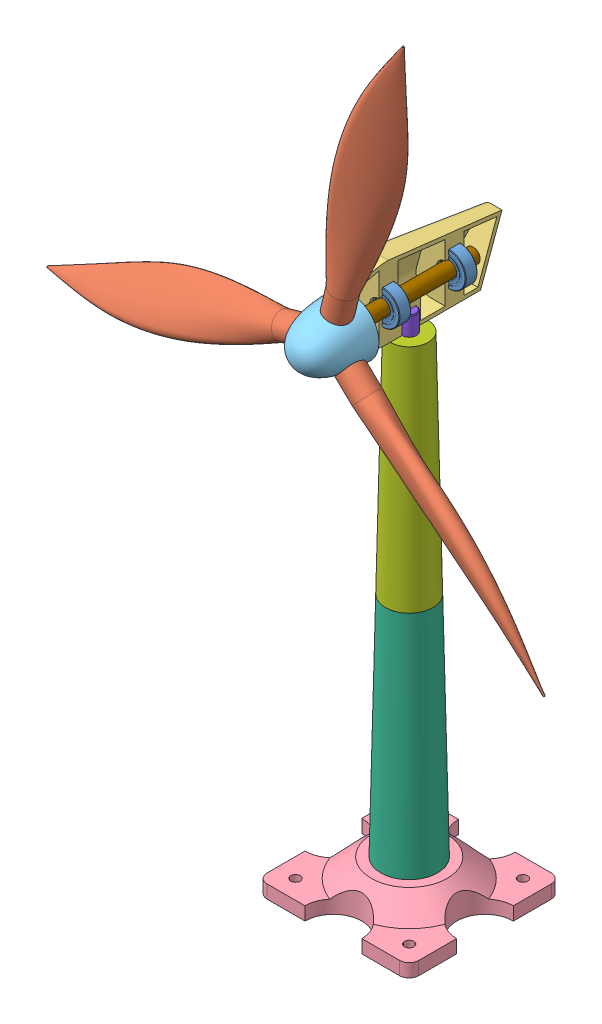
SolidWorks assembly WindTurbine, configuration Default. Lengths in mm.
Overall size (355.91 547.34 141.48).
12 component instances, 9 part files, 20 mates.
Components (placement in the parent):
- 6384K56_Ball Bearing-1: 6384K56_Ball Bearing [6384K56] at origin size (23.02 23.02 7.94)
- blade-1: blade [Default] at (5.4942 -5.28 37.9413) x (0.651126 0.677538 0.34202) z (0.23699 0.246604 -0.939693) size (42.91 190.51 16.85)
- Nacelle turbine-1: Nacelle turbine [Default] at (0 0 -0.1588) size (28.12 50.72 103.39)
- Turbine Base-1: Turbine Base [Default] at (0 -349.25 -14.1288) size (101.6 21.59 101.6)
- turbine hub-1: turbine hub [Default] at (0 0 63.3413) x (-0.692914 -0.721021 0) z (0 0 1) size (38.26 38.57 38.1)
- wind turbine lower mast-1: wind turbine lower mast [Default] at (0 -340.36 -14.1288) x (0 1 0) z (0 0 1) size (165.1 38.1 38.1)
- wind turbine upper mast-1: wind turbine upper mast [Default] at (0 -175.26 -14.1288) x (0 1 0) z (0 0 1) size (165.1 31.75 31.75)
- 6384K56_Ball Bearing-2: 6384K56_Ball Bearing [6384K56] at (0 0 -44.45) size (23.02 23.02 7.94)
- blade-5: blade [Default] at (-7.3197 -2.1181 37.9413) x (0.261202 -0.90266 0.34202) z (0.09507 -0.328541 -0.939693) size (42.91 190.51 16.85)
- blade-6: blade [Default] at (1.8255 7.3981 37.9413) x (-0.912328 0.225122 0.34202) z (-0.33206 0.081938 -0.939693) size (42.91 190.51 16.85)
- wind turbine swivel-2: wind turbine swivel [Default] at (0 -29.21 -14.1288) size (9.65 38.1 9.65)
- wind turbine main shaft-2: wind turbine main shaft [Default] at (0 0 -9.6837) x (1 0 0) z (0 -1 0) size (9.65 95.25 9.65)
Mates (geometry in assembly coordinates):
- Concentric1: concentric anti-aligned: cylinder of Turbine Base-1 through (0 -340.36 -14.1288) axis (0 1 0) radius 19.05; cylinder of wind turbine lower mast-1 through (0 -340.36 -14.1288) axis (0 -1 0) radius 19.05
- Coincident1: coincident anti-aligned: plane of Turbine Base-1 through (0 -340.36 -14.1288) normal (0 1 0); plane of wind turbine lower mast-1 through (-19.05 -340.36 -14.1288) normal (0 -1 0)
- Coincident3: coincident anti-aligned: plane of wind turbine lower mast-1 through (0 -187.96 -14.1288) normal (0 1 0); plane of wind turbine upper mast-1 through (0 -187.96 -14.1288) normal (0 -1 0)
- Coincident4: coincident aligned: cone of wind turbine lower mast-1 through (0 -175.26 -14.1288) axis (0 1 0); cone of wind turbine upper mast-1 through (0 -22.86 -14.1288) axis (0 1 0)
- Tangent1: tangent: plane of assembly; face of Nacelle turbine-1; plane of wind turbine upper mast-1 through (0 -22.86 -14.1288) normal (0 1 0)
- Concentric2: concentric anti-aligned: cylinder of Nacelle turbine-1 through (0 -22.86 -14.1288) axis (0 -1 0) radius 4.826; cylinder of wind turbine upper mast-1 through (0 -48.26 -14.1288) axis (0 1 0) radius 4.826
- Concentric3: concentric aligned: circle of Nacelle turbine-1; circle of turbine hub-1
- Coincident5: coincident anti-aligned: plane of Nacelle turbine-1 through (0 0 25.2413) normal (0 0 1); plane of turbine hub-1 through (0 0 25.2413) normal (0 0 -1)
- Coincident6: coincident anti-aligned: plane of blade-1 through (5.4942 -5.28 37.9413) normal (-0.721021 0.692914 0); plane of turbine hub-1 through (5.4942 -5.28 37.9413) normal (0.721021 -0.692914 0)
- Concentric4: concentric aligned: cylinder of blade-1 through (23.8081 -22.88 37.9413) axis (-0.721021 0.692914 0) radius 8.255; cylinder of turbine hub-1 through (17.2151 -16.544 37.9413) axis (-0.721021 0.692914 0) radius 8.255
- Concentric5: concentric aligned: cylinder of 6384K56_Ball Bearing-1 through (0 0 3.9688) axis (0 0 1) radius 4.7625; cylinder of Nacelle turbine-1 through (0 0 33.2282) axis (0 0 1) radius 11.43
- Coincident7: coincident anti-aligned: plane of 6384K56_Ball Bearing-1 through (0 11.1125 -3.9688) normal (0 0 -1); plane of Nacelle turbine-1 through (0 5.8691 -3.9688) normal (0 0 1)
- Parallel1: parallel anti-aligned: plane of Turbine Base-1 through (-44.45 -349.25 30.3213) normal (0 -1 0)
- Concentric11: concentric aligned: cylinder of Nacelle turbine-1 through (0 0 33.2282) axis (0 0 1) radius 11.43; cylinder of 6384K56_Ball Bearing-2 through (0 0 -40.4813) axis (0 0 1) radius 11.5094
- Coincident13: coincident anti-aligned: plane of Nacelle turbine-1 through (0 5.8691 -48.4188) normal (0 0 1); plane of 6384K56_Ball Bearing-2 through (0 11.1125 -48.4188) normal (0 0 -1)
- Angle5: planar angle = 5.061455 rad anti-aligned: plane of blade-1 through (5.4942 -5.28 37.9413) normal (0.651126 0.677538 0.34202); plane of turbine hub-1 through (0 0 25.2413) normal (0 0 -1)
- Coincident18: coincident anti-aligned: plane of wind turbine upper mast-1 through (0 -48.26 -14.1288) normal (0 1 0); plane of wind turbine swivel-2 through (0 -48.26 -14.1288) normal (0 -1 0)
- Concentric12: concentric aligned: cylinder of Nacelle turbine-1 through (0 -22.86 -14.1288) axis (0 -1 0) radius 4.826; cylinder of wind turbine swivel-2 through (0 -10.16 -14.1288) axis (0 -1 0) radius 4.826
- Concentric13: concentric anti-aligned: circle of 6384K56_Ball Bearing-2; cylinder of wind turbine main shaft-2 through (0 0 37.9413) axis (0 0 -1) radius 4.826
- Coincident19: coincident anti-aligned: plane of turbine hub-1 through (0 0 37.9413) normal (0 0 -1); plane of wind turbine main shaft-2 through (0 0 37.9413) normal (0 0 1)
